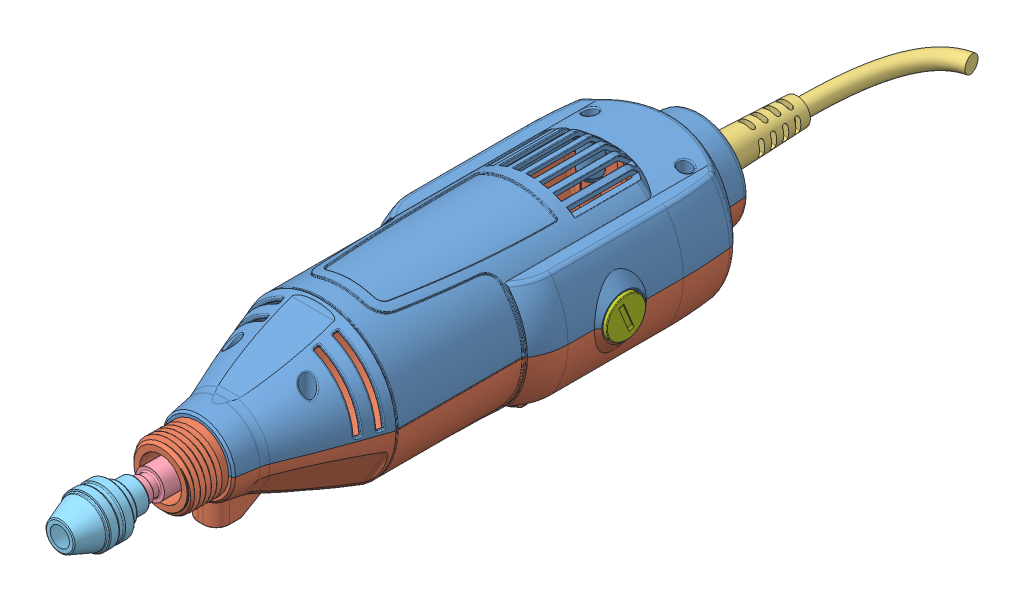
SolidWorks assembly Dremel Assembly, configuration Default. Lengths in mm.
Overall size (56.71 52.89 264.48).
8 component instances, 7 part files, 15 mates.
Components (placement in the parent):
- Dremel Left Half-1: Dremel Left Half [Default] at origin size (55.12 24.36 152.4)
- Dremel Right Half-1: Dremel Right Half [Default] x (-1 0 0) z (0 0 1) size (55.12 36.04 163.96)
- Dremel Chord-1: Dremel Chord [Default] at (0 0 -144.4625) x (1 0 0) z (0 1 0) size (22.66 78.4 16.21)
- Dremel Chuck Mount-1: Dremel Chuck Mount [Default] at (0 0 -7.9375) x (0.325874 -0.945413 0) z (-0.945413 -0.325874 0) size (8.71 38.1 8.71)
- Dremel Chuck-1: Dremel Chuck [Default] at (0 0 19.0627) x (0.99596 -0.0898 0) z (-0.0898 -0.99596 0) size (15.24 22.56 15.24)
- Dremel Speed Lever-1: Dremel Speed Lever [Default] at (0 0 -93.09) x (-0.965324 -0.261055 0) z (0 0 1) size (27.22 10.71 7.94)
- Dremel Motor Adjust-1: Dremel Motor Adjust [Default] at (-22.0028 0 -101.6) x (0 0.384439 -0.92315) z (1 0 0) size (11.91 11.91 6.35)
- Dremel Motor Adjust-2: Dremel Motor Adjust [Default] at (22.0028 0 -101.6) x (0 -0.384439 0.92315) z (-1 0 0) size (11.91 11.91 6.35)
Mates (geometry in assembly coordinates):
- Coincident1: coincident anti-aligned: plane of Dremel Left Half-1 through (93.8758 0 -66.675) normal (0 -1 0); plane of Dremel Right Half-1 through (-93.8758 0 -66.675) normal (0 1 0)
- Coincident2: coincident anti-aligned: plane of Dremel Left Half-1 through (0 0 0) normal (1 0 0); plane of Dremel Right Half-1 through (0 0 0) normal (-1 0 0)
- Coincident3: coincident aligned: plane of Dremel Left Half-1 through (0 0 0) normal (0 0 1); plane of Dremel Right Half-1 through (0 0 0) normal (0 0 1)
- Concentric1: concentric aligned: cylinder of Dremel Left Half-1 through (0 0 -152.4) axis (0 0 1) radius 6.35; cylinder of Dremel Chord-1 through (0 0 -144.4625) axis (0 0 1) radius 7.1437
- Coincident4: coincident anti-aligned: plane of Dremel Right Half-1 through (0 0 -152.4) normal (0 0 -1); plane of Dremel Chord-1 through (5.9531 0 -152.4) normal (0 0 1)
- Concentric2: concentric anti-aligned: cylinder of Dremel Right Half-1 through (0 0 -152.4) axis (0 0 1) radius 6.35; cylinder of Dremel Chuck Mount-1 through (0 0 -7.9375) axis (0 0 -1) radius 4.3561
- Distance1: distance = 19.05 mm aligned: plane of Dremel Chuck Mount-1 through (1.1381 -3.3019 30.1625) normal (0 0 1); plane of Dremel Right Half-1 through (-8.1085 0 11.1125) normal (0 0 1)
- Concentric4: concentric aligned: cylinder of Dremel Chuck Mount-1 through (0 0 -7.9375) axis (0 0 -1) radius 3.4925; cylinder of Dremel Chuck-1 through (0 0 19.0627) axis (0 0 -1) radius 3.3782
- Distance2: distance = 12.7 mm anti-aligned: plane of Dremel Right Half-1 through (-8.1085 0 11.1125) normal (0 0 1); plane of Dremel Chuck-1 through (5.7552 -0.5189 23.8125) normal (0 0 -1)
- Concentric5: concentric aligned: cone of Dremel Chuck-1 through (0 0 41.6179) axis (0 0 1); cylinder of ? through (0 0 55.5625) axis (0 0 1) radius 1.5875
- Coincident7: coincident anti-aligned: plane of Dremel Chuck Mount-1 through (1.1381 -3.3019 30.1625) normal (0 0 1); plane of ? through (0 0 30.1625) normal (0 0 -1)
- Coincident8: coincident aligned: plane of Dremel Right Half-1 through (0 0 -93.09) normal (0 0 1); plane of Dremel Speed Lever-1 through (0 0 -93.09) normal (0 0 1)
- Concentric6: concentric aligned: cylinder of Dremel Right Half-1 through (0 0 -133.35) axis (0 0 -1) radius 22.2726; cylinder of Dremel Speed Lever-1 through (0 0 -89.1213) axis (0 0 -1) radius 21.9075
- Concentric7: concentric anti-aligned: cylinder of Dremel Right Half-1 through (-25.9715 0 -101.6) axis (-1 0 0) radius 6.35; cylinder of Dremel Motor Adjust-1 through (-22.0028 0 -101.6) axis (1 0 0) radius 5.9531
- Coincident9: coincident anti-aligned: plane of Dremel Right Half-1 through (-25.9715 0 -101.6) normal (-1 0 0); plane of Dremel Motor Adjust-1 through (-25.9715 2.2886 -107.0956) normal (1 0 0)
